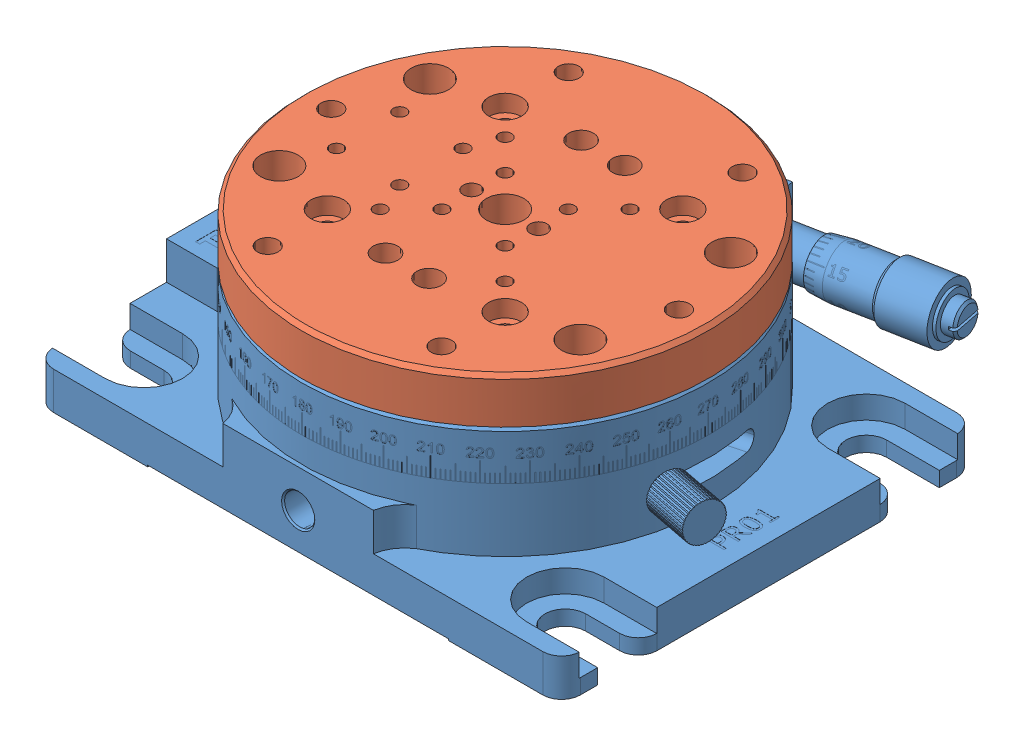
SolidWorks assembly PR01 + adaptor, configuration Default. Lengths in mm.
Overall size (88.9 32.89 82.68).
2 component instances, 2 part files, 2 mates.
Components (placement in the parent):
- PR01-Solidworks-1: PR01-Solidworks [Default] at (32.836 6.2197 50.44) size (88.9 25.27 82.68)
- PR01A-Solidworks-1: PR01A-Solidworks [Default] at (20.0486 45.6101 48.8975) size (68.58 7.62 68.58)
Mates (geometry in assembly coordinates):
- Concentric5: concentric anti-aligned: circle of PR01-Solidworks-1; circle of PR01A-Solidworks-1
- Coincident1: coincident anti-aligned: plane of PR01-Solidworks-1 through (16.3362 41.0289 51.3778) normal (0 1 0); plane of PR01A-Solidworks-1 through (16.3362 41.0289 51.3804) normal (0 -1 0)
